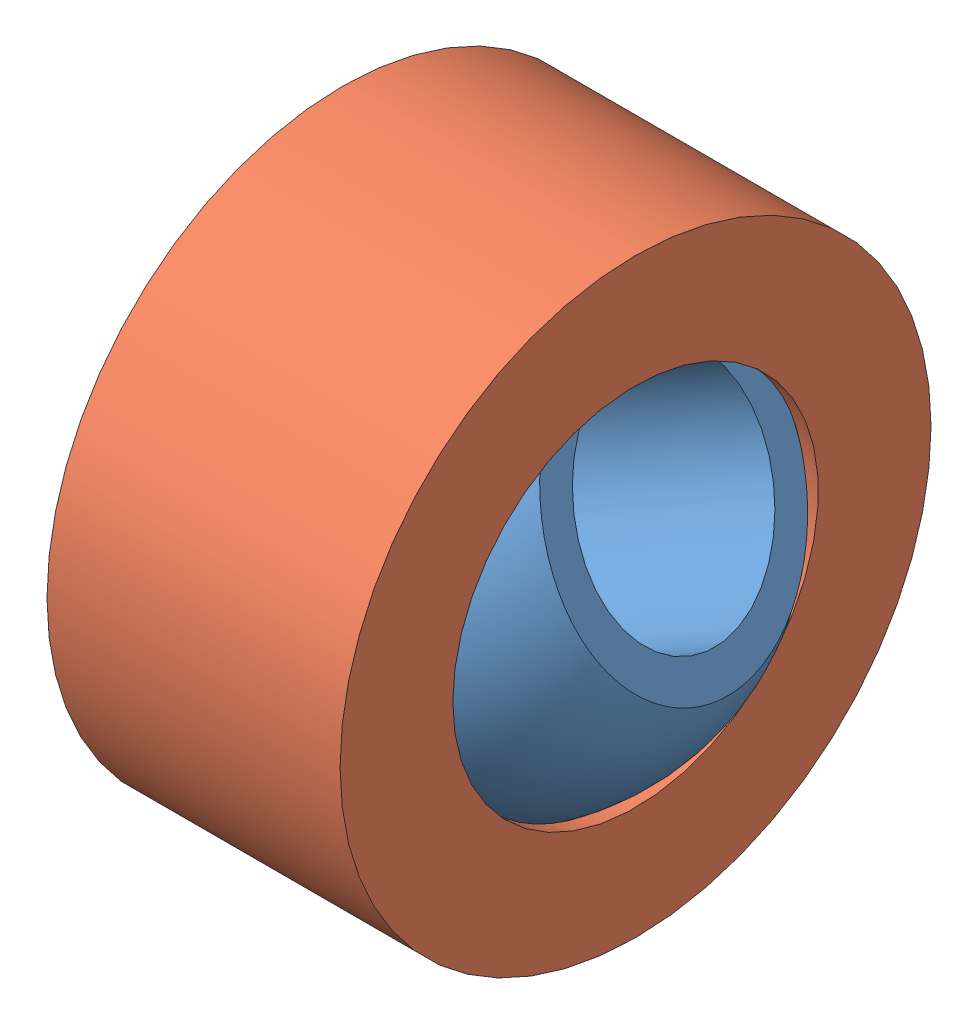
SolidWorks assembly Bearing, configuration Default. Lengths in mm.
Overall size (23.25 31.46 29.59).
2 component instances, 2 part files, 1 mates.
Components (placement in the parent):
- Ball-1: Ball [Default] at (30.7023 7.7326 -10.1272) x (0.88682 0.414048 -0.205219) z (0.460641 -0.756594 0.464086) size (15 20 20)
- Ring-1: Ring [Default] at (30.7023 15.8397 -10.1272) size (13 26.21 26.21)
Mates (geometry in assembly coordinates):
- Concentric1: concentric: sphere of Bearing-1; sphere of Ring-1
